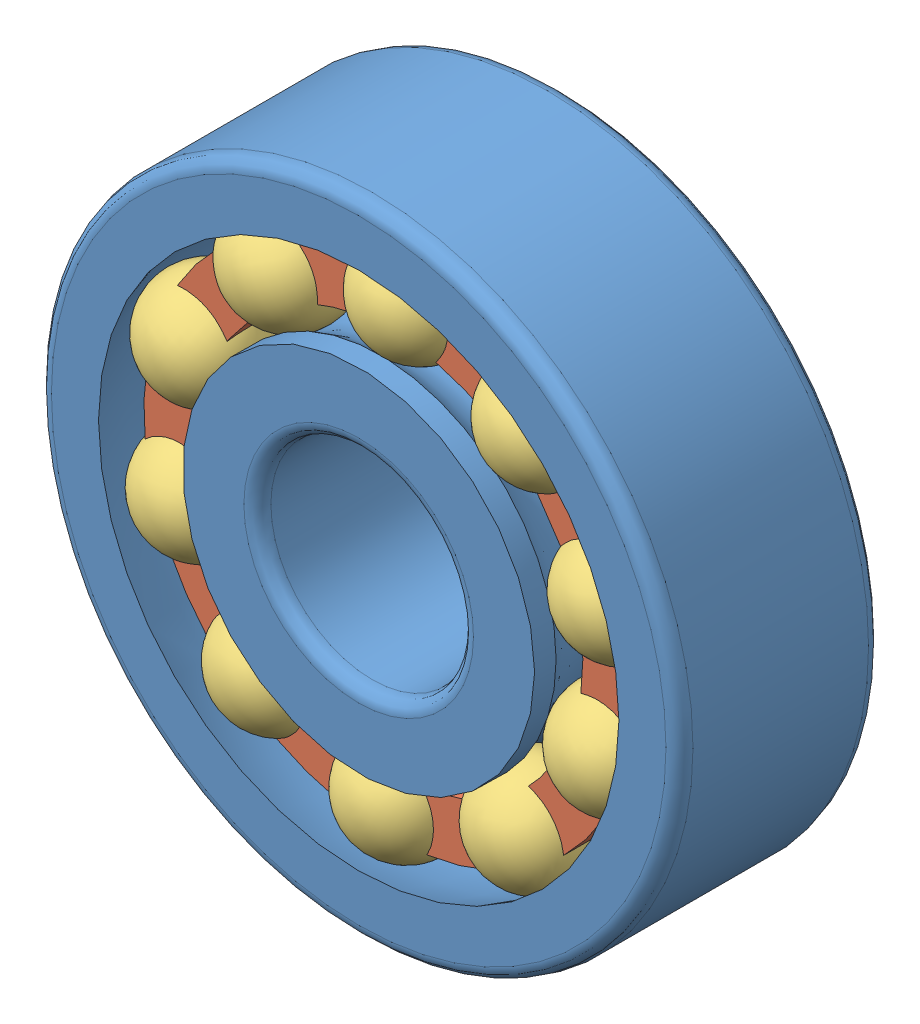
SolidWorks assembly Подшипник_126_ACC_ISB, configuration По умолчанию. Lengths in mm.
Overall size (20.31 20.31 7.34).
22 component instances, 3 part files, 5 mates.
Components (placement in the parent):
- Корпус_126_ACC_ISB-1: Корпус_126_ACC_ISB [По умолчанию] at origin size (19 19 6)
- Сепаратор_126_ACC_ISB-1: Сепаратор_126_ACC_ISB [По умолчанию] at (0 0 -0.75) x (-0.827915 -0.560854 0) z (0 0 1) size (14.62 14.62 4.28)
- Шарик_126_ACC_ISB-1: Шарик_126_ACC_ISB [По умолчанию] at (-3.6455 5.3814 -1.625) x (-0.551094 0.71689 -0.427042) z (0.831329 0.427513 -0.355141) size (3.25 3.25 3.25)
- Шарик_126_ACC_ISB-11: Шарик_126_ACC_ISB [По умолчанию] at (-1.8042 6.2446 -4.37) x (0.406154 -0.907355 -0.10838) z (-0.150045 0.050775 -0.987375) size (3.25 3.25 3.25)
- Шарик_126_ACC_ISB-21: Шарик_126_ACC_ISB [По умолчанию] at (-6.1124 2.2109 -1.625) x (-0.867221 0.256051 -0.427042) z (0.421273 0.834508 -0.355141) size (3.25 3.25 3.25)
- Шарик_126_ACC_ISB-22: Шарик_126_ACC_ISB [По умолчанию] at (-6.2446 -1.8042 -1.625) x (-0.8521 -0.30259 -0.427042) z (-0.149694 0.922749 -0.355141) size (3.25 3.25 3.25)
- Шарик_126_ACC_ISB-23: Шарик_126_ACC_ISB [По умолчанию] at (-3.9915 -5.1301 -1.625) x (-0.511505 -0.745652 -0.427042) z (-0.663484 0.658532 -0.355141) size (3.25 3.25 3.25)
- Шарик_126_ACC_ISB-24: Шарик_126_ACC_ISB [По умолчанию] at (-0.2138 -6.4965 -1.625) x (0.024467 -0.903901 -0.427042) z (-0.923845 0.142777 -0.355141) size (3.25 3.25 3.25)
- Шарик_126_ACC_ISB-25: Шарик_126_ACC_ISB [По умолчанию] at (3.6455 -5.3814 -1.625) x (0.551094 -0.71689 -0.427042) z (-0.831329 -0.427513 -0.355141) size (3.25 3.25 3.25)
- Шарик_126_ACC_ISB-26: Шарик_126_ACC_ISB [По умолчанию] at (6.1124 -2.2109 -1.625) x (0.867221 -0.256051 -0.427042) z (-0.421273 -0.834508 -0.355141) size (3.25 3.25 3.25)
- Шарик_126_ACC_ISB-27: Шарик_126_ACC_ISB [По умолчанию] at (6.2446 1.8042 -1.625) x (0.8521 0.30259 -0.427042) z (0.149694 -0.922749 -0.355141) size (3.25 3.25 3.25)
- Шарик_126_ACC_ISB-28: Шарик_126_ACC_ISB [По умолчанию] at (3.9915 5.1301 -1.625) x (0.511505 0.745652 -0.427042) z (0.663484 -0.658532 -0.355141) size (3.25 3.25 3.25)
- Шарик_126_ACC_ISB-29: Шарик_126_ACC_ISB [По умолчанию] at (0.2138 6.4965 -1.625) x (-0.024467 0.903901 -0.427042) z (0.923845 -0.142777 -0.355141) size (3.25 3.25 3.25)
- Шарик_126_ACC_ISB-30: Шарик_126_ACC_ISB [По умолчанию] at (-5.1301 3.9915 -4.37) x (0.861915 -0.495334 -0.10838) z (-0.151233 -0.047116 -0.987375) size (3.25 3.25 3.25)
- Шарик_126_ACC_ISB-31: Шарик_126_ACC_ISB [По умолчанию] at (-6.4965 0.2138 -4.37) x (0.988454 0.105887 -0.10838) z (-0.094656 -0.12701 -0.987375) size (3.25 3.25 3.25)
- Шарик_126_ACC_ISB-32: Шарик_126_ACC_ISB [По умолчанию] at (-5.3814 -3.6455 -4.37) x (0.737437 0.666663 -0.10838) z (-0.001924 -0.158391 -0.987375) size (3.25 3.25 3.25)
- Шарик_126_ACC_ISB-33: Шарик_126_ACC_ISB [По умолчанию] at (-2.2109 -6.1124 -4.37) x (0.204744 0.972797 -0.10838) z (0.091544 -0.129272 -0.987375) size (3.25 3.25 3.25)
- Шарик_126_ACC_ISB-34: Шарик_126_ACC_ISB [По умолчанию] at (1.8042 -6.2446 -4.37) x (-0.406154 0.907355 -0.10838) z (0.150045 -0.050775 -0.987375) size (3.25 3.25 3.25)
- Шарик_126_ACC_ISB-35: Шарик_126_ACC_ISB [По умолчанию] at (5.1301 -3.9915 -4.37) x (-0.861915 0.495334 -0.10838) z (0.151233 0.047116 -0.987375) size (3.25 3.25 3.25)
- Шарик_126_ACC_ISB-36: Шарик_126_ACC_ISB [По умолчанию] at (6.4965 -0.2138 -4.37) x (-0.988454 -0.105887 -0.10838) z (0.094656 0.12701 -0.987375) size (3.25 3.25 3.25)
- Шарик_126_ACC_ISB-37: Шарик_126_ACC_ISB [По умолчанию] at (5.3814 3.6455 -4.37) x (-0.737437 -0.666663 -0.10838) z (0.001924 0.158391 -0.987375) size (3.25 3.25 3.25)
- Шарик_126_ACC_ISB-38: Шарик_126_ACC_ISB [По умолчанию] at (2.2109 6.1124 -4.37) x (-0.204744 -0.972797 -0.10838) z (-0.091544 0.129272 -0.987375) size (3.25 3.25 3.25)
Mates (geometry in assembly coordinates):
- Концентричный1: concentric: sphere of Сепаратор_126_ACC_ISB-1; sphere of Шарик_126_ACC_ISB-1
- Концентричный2: concentric: sphere of Сепаратор_126_ACC_ISB-1; sphere of Шарик_126_ACC_ISB-11
- Концентричный3: concentric aligned: cylinder of Корпус_126_ACC_ISB-1 through (0 0 0) axis (0 0 1) radius 3; cylinder of Сепаратор_126_ACC_ISB-1 through (0 0 -0.75) axis (0 0 1) radius 5.6875
- Параллельность1: parallel aligned: plane of Корпус_126_ACC_ISB-1 through (0 9.5 0) normal (0 0 1); plane of Сепаратор_126_ACC_ISB-1 through (0 0 -0.95) normal (0 0 1)
- Касательность1: tangent: torus of Корпус_126_ACC_ISB-1; sphere of Шарик_126_ACC_ISB-1
